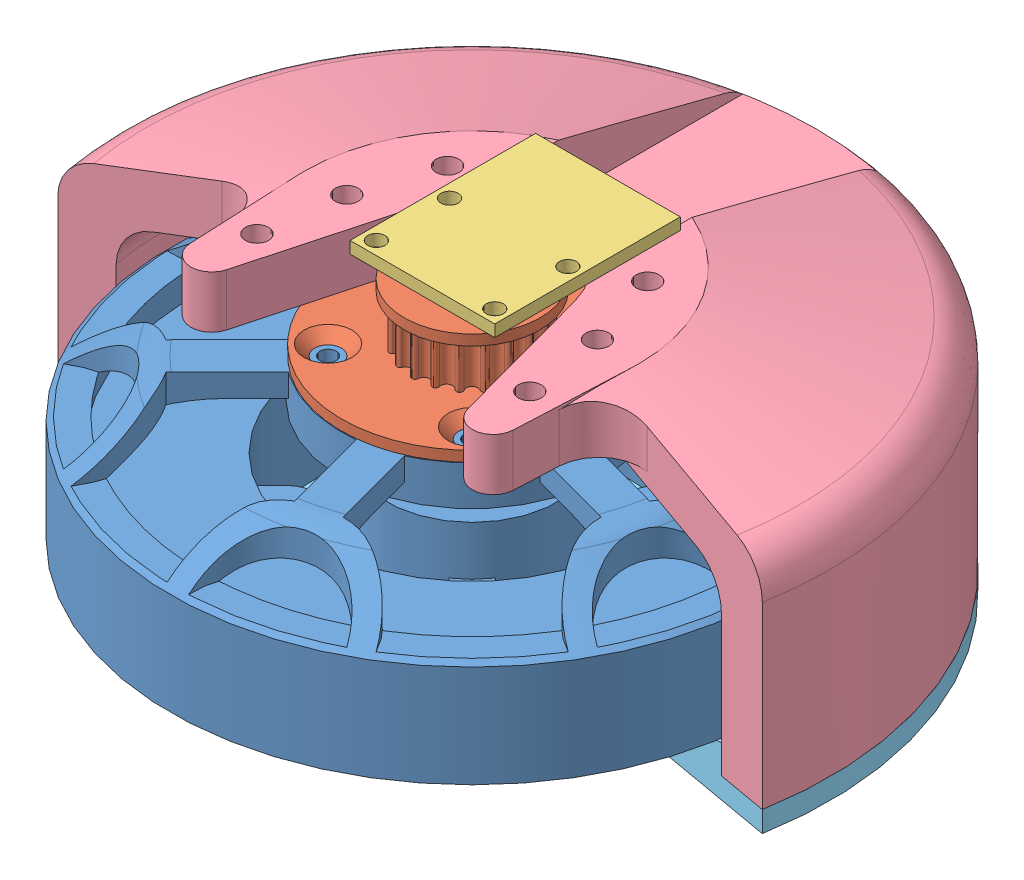
SolidWorks assembly MotorPulleyHall, configuration Default. Lengths in mm.
Overall size (129.63 52.01 129.63).
5 component instances, 5 part files, 10 mates.
Components (placement in the parent):
- 9225 160kv-1: 9225 160kv [Default] at (0 -3.93 0) x (0.707107 0 0.707107) z (-0.707107 0 0.707107) size (91.66 44.53 91.66)
- 20 tooth htd 3mm pulley-1: 20 tooth htd 3mm pulley [Default] at (0 33.3375 0) x (0.707107 0 0.707107) z (-0.707107 0 0.707107) size (39.69 10.17 39.69)
- AS5047D Dev Board-1: AS5047D Dev Board [Default] at (0 41.7308 0) x (-1 0 0) z (0 0 1) size (22 6.88 28.22)
- Copy of Part1^MotorPulleyHall-1: Copy of Part1^MotorPulleyHall [Default] at (0 65.7833 0) x (-1 0 0) z (0 0 1) size (108.81 39.93 75.78) (virtual)
- MotorMountPlate-1: MotorMountPlate [Default] at origin size (114.06 7.53 81.9)
Mates (geometry in assembly coordinates):
- Coincident2: coincident aligned: line of 9225 160kv-1 through (41.998 0 36.159) axis (0 0 -1)
- Coincident3: coincident anti-aligned: plane of 9225 160kv-1 through (6.8236 0 6.8236) normal (0 -1 0)
- Angle1: planar angle = 0.785398 rad aligned: plane of 9225 160kv-1 through (0 -3.93 0) normal (-0.707107 0 0.707107)
- Coincident12: coincident: point of AS5047D Dev Board-1
- Concentric4: concentric aligned: cylinder of 9225 160kv-1 through (0 34.25 0) axis (0 1 0) radius 1.5; cylinder of 15 tooth htd 3mm pulley-1 through (0 35.25 0) axis (0 1 0) radius 3.175
- Concentric5: concentric anti-aligned: cylinder of 9225 160kv-1 through (-10.9602 28.25 10.9602) axis (0 1 0) radius 1.25; cone of 15 tooth htd 3mm pulley-1 through (-10.9602 26.2053 10.9602) axis (0 -1 0)
- Coincident14: coincident anti-aligned: plane of 9225 160kv-1 through (22.981 28.25 22.981) normal (0 1 0); plane of 15 tooth htd 3mm pulley-1 through (0 28.25 0) normal (0 -1 0)
- Parallel1: parallel anti-aligned: plane of AS5047D Dev Board-1 through (0 39.9308 0) normal (0 -1 0)
- Coincident16: coincident anti-aligned: plane of AS5047D Dev Board-1 through (0 41.7308 0) normal (-1 0 0)
- Coincident20: coordinate: point of assembly; point of MotorMountPlate-1; point of assembly
